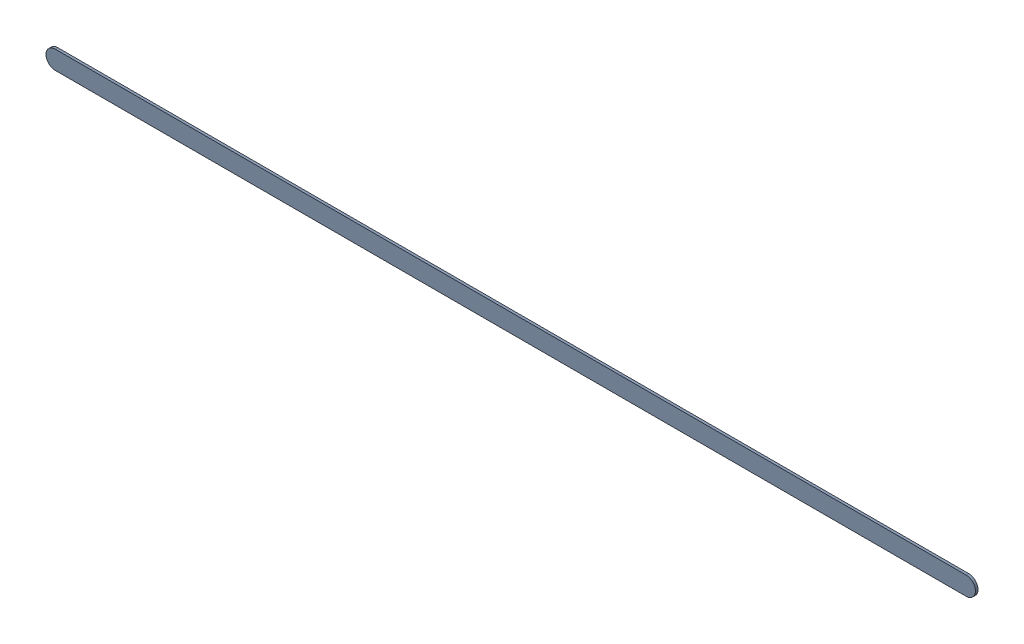
SolidWorks assembly Track (13.8mm,6.3mm)(26.366mm,6.3mm) on Top Layer, configuration Predeterminado. Lengths in mm.
Overall size (12.82 0.25 0.04).
2 component instances, 1 part files, 0 mates.
Components (placement in the parent):
- Track (13.8mm,6.3mm)(26.366mm,6.3mm) on Top Layer-1-1: Track (13.8mm,6.3mm)(26.366mm,6.3mm) on Top Layer-1 [Predeterminado] at (-68.317 -44.187 -0.0457) size (12.82 0.25 0.04)
  - Track (13.8mm,6.3mm)(26.366mm,6.3mm) on Top Layer-Part-1-1: Track (13.8mm,6.3mm)(26.366mm,6.3mm) on Top Layer-Part-1 [Predeterminado] at origin size (12.82 0.25 0.04)
